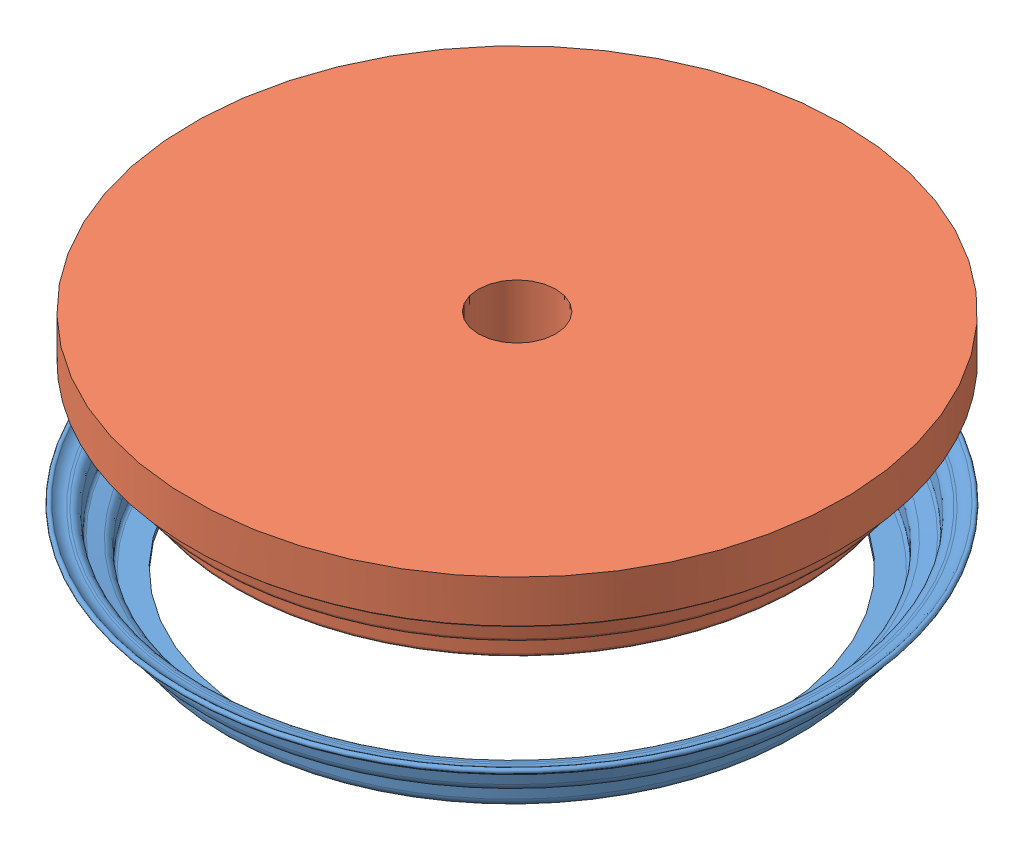
SolidWorks assembly buck-spun, configuration Default. Lengths in mm.
Overall size (441.6 190.41 438.18).
2 component instances, 2 part files, 0 mates.
Components (placement in the parent):
- spun wheel125-2-1: spun wheel125-2 [Default] at origin size (432.05 41.65 432.05)
- buck Main^buck-spun-1: buck Main^buck-spun [Default] at (12.2688 90.743 8.8503) size (426.62 99.67 426.62) (virtual)
